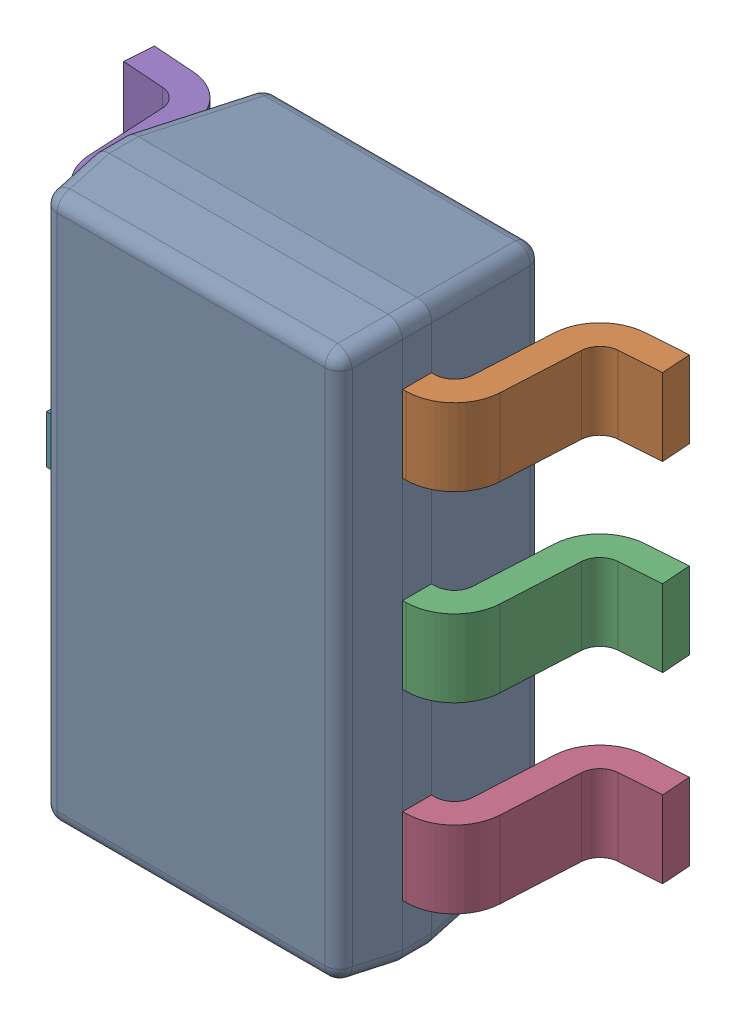
SolidWorks assembly IC18_1.step, configuration Default. Lengths in mm.
Overall size (2.8 2.9 1.2).
8 component instances, 3 part files, 0 mates.
Components (placement in the parent):
- 6348794768_1.step-11: 6348794768_1.step [Default] at (389.9005 305.0466 0) x (-1 0 0) z (0 0 1) size (2.8 2.9 1.2)
  - BODY-SOT-9_1.step-11: BODY-SOT-9_1.step [Default] at (0 0 0.9) x (0 -1 0) z (-1 0 0) size (2.9 1.1 1.6)
  - LEAD-SOT-10_1.step-53: LEAD-SOT-10_1.step [Default] at (-0.9395 -0.95 0.25) x (0 -1 0) z (-1 0 0) size (0.4 0.9 0.6)
  - LEAD-SOT-10_1.step-54: LEAD-SOT-10_1.step [Default] at (-0.9395 0 0.25) x (0 -1 0) z (-1 0 0) size (0.4 0.9 0.6)
  - LEAD-SOT-10_1.step-55: LEAD-SOT-10_1.step [Default] at (-0.9395 0.95 0.25) x (0 -1 0) z (-1 0 0) size (0.4 0.9 0.6)
  - LEAD-SOT-10_1.step-56: LEAD-SOT-10_1.step [Default] at (0.9395 -0.95 0.25) x (0 1 0) z (1 0 0) size (0.4 0.9 0.6)
  - LEAD-SOT-10_1.step-57: LEAD-SOT-10_1.step [Default] at (0.9395 0.95 0.25) x (0 1 0) z (1 0 0) size (0.4 0.9 0.6)
  - LEAD-DUMMY-11_1.step-11: LEAD-DUMMY-11_1.step [Default] at (1.05 0 0.76) x (0 -1 0) z (-1 0 0) size (0.25 0.14 0.25)
